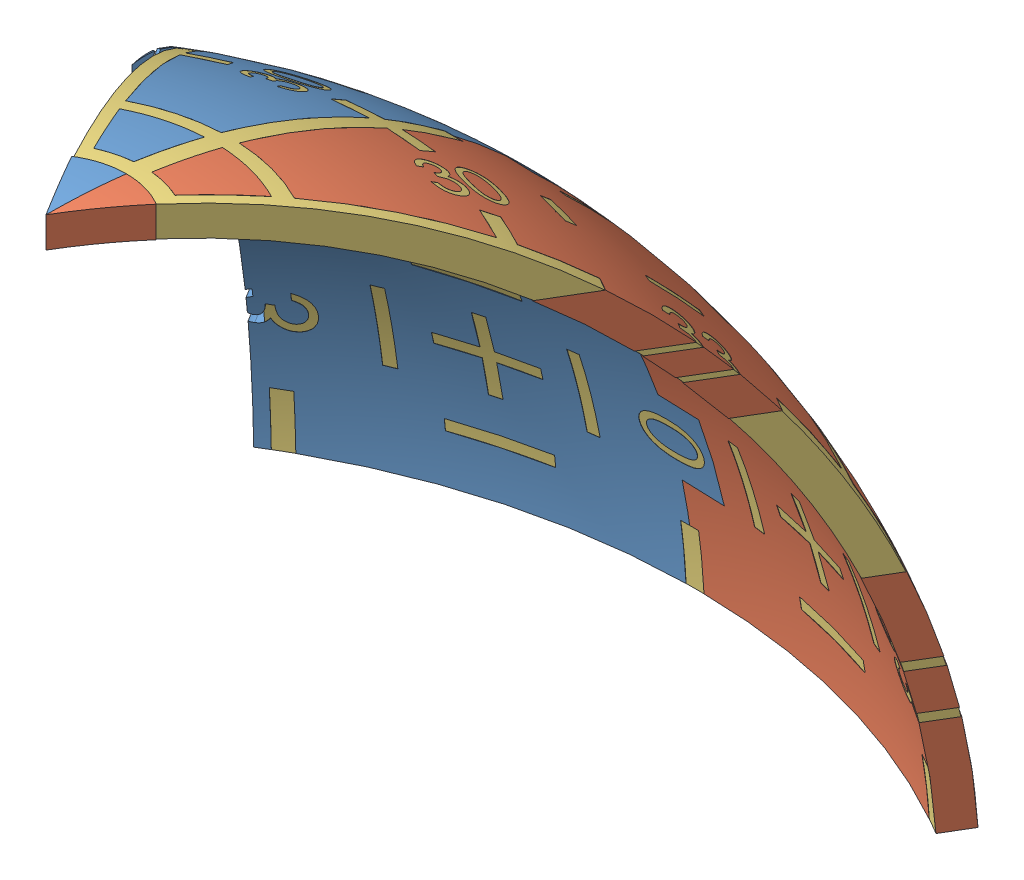
SolidWorks assembly Testpuzzle, configuration Default. Lengths in mm.
Overall size (183.03 89.81 183.03).
3 component instances, 3 part files, 4 mates.
Components (placement in the parent):
- TestTopWhiteOuter-1: TestTopWhiteOuter [Default] at (34.8611 45.3576 67.9155) size (148.6 44.45 148.6)
- TestTopBlackOuter-1: TestTopBlackOuter [Default] at (34.8611 45.3576 67.9155) size (164.71 44.45 164.71)
- TestTopPlug-1: TestTopPlug [Default] at (34.8611 45.4076 67.9155) size (161.26 44.09 161.26)
Mates (geometry in assembly coordinates):
- Coincident1: coincident: circle of TestTopWhiteOuter-1; circle of TestTopBlackOuter-1
- Coincident5: coincident: plane of TestTopWhiteOuter-1 through (34.8611 47.4576 67.9155) normal (0 -1 0); plane of TestTopBlackOuter-1 through (34.8611 47.4576 67.9155) normal (0 -1 0)
- Coincident13: coincident: plane of TestTopBlackOuter-1 through (34.8611 47.4576 67.9155) normal (0 -1 0); plane of TestTopPlug-1 through (93.9891 47.4576 23.5155) normal (0 -1 0)
- Coincident14: coincident: plane of TestTopWhiteOuter-1 through (34.8611 47.4576 67.9155) normal (0 -1 0); plane of TestTopPlug-1 through (93.9891 47.4576 23.5155) normal (0 -1 0)
